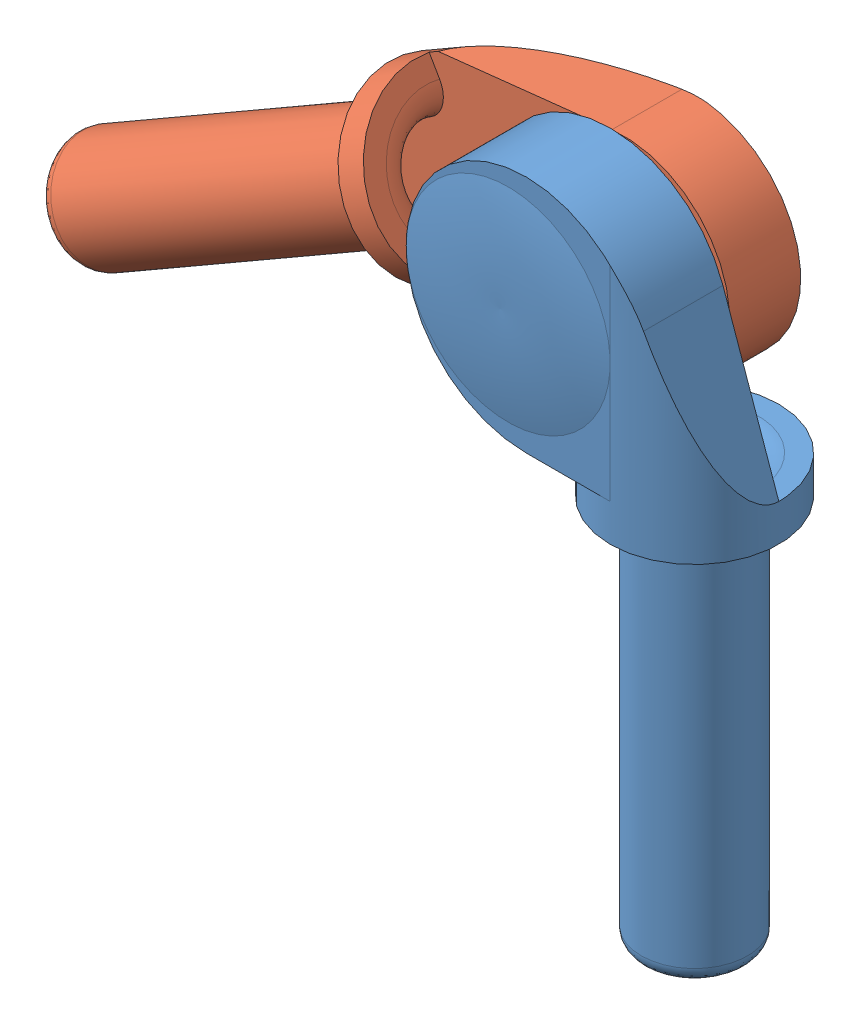
SolidWorks assembly class2_joint, configuration 默认. Lengths in mm.
Overall size (27.28 28 6.67).
2 component instances, 2 part files, 3 mates.
Components (placement in the parent):
- joint_bearing-1: joint_bearing [默认] at origin size (10.85 25 6.67)
- joint_shaft-1: joint_shaft [默认] at (-22.516 12.9996 0) x (-0.5 0.866025 0) z (0 0 -1) size (10.35 24.5 6.35)
Mates (geometry in assembly coordinates):
- 同心1: concentric anti-aligned: cylinder of joint_bearing-1 through (-3.175 20.5 2.775) axis (0 0 -1) radius 3.15; cylinder of joint_shaft-1 through (-3.175 20.5 -2.5) axis (0 0 1) radius 1.65
- 同心2: concentric anti-aligned: cylinder of joint_bearing-1 through (-3.175 20.5 2.775) axis (0 0 -1) radius 3.15; cylinder of joint_shaft-1 through (-3.175 20.5 -2.5) axis (0 0 1) radius 1.65
- 距离1: distance = 0.5 mm anti-aligned: plane of joint_bearing-1 through (-3.175 20.5 0) normal (0 0 -1); plane of joint_shaft-1 through (-2.8859 27.9993 -0.5) normal (0 0 1)
